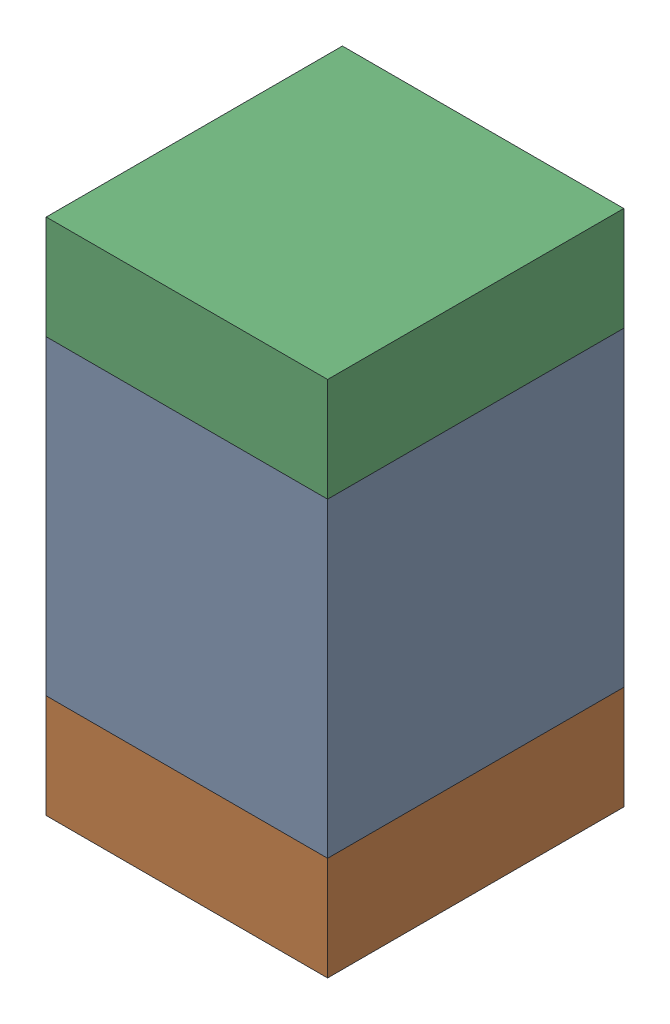
SolidWorks assembly C9-2, configuration Default. Lengths in mm.
Overall size (0.95 1.75 1).
6 component instances, 2 part files, 0 mates.
Components (placement in the parent):
- 959208528-2-1: 959208528-2 [Default] at (108.577 76.835 0) size (0.95 1.05 1)
  - Extruded-77-1: Extruded-77 [Default] at origin size (0.95 1.05 1)
- 959208664-2-1: 959208664-2 [Default] at (108.577 76.135 0) size (0.95 0.35 1)
  - Extruded-76-1: Extruded-76 [Default] at origin size (0.95 0.35 1)
- 959208664-2-2: 959208664-2 [Default] at (108.577 77.535 0) size (0.95 0.35 1)
  - Extruded-76-1: Extruded-76 [Default] at origin size (0.95 0.35 1)
